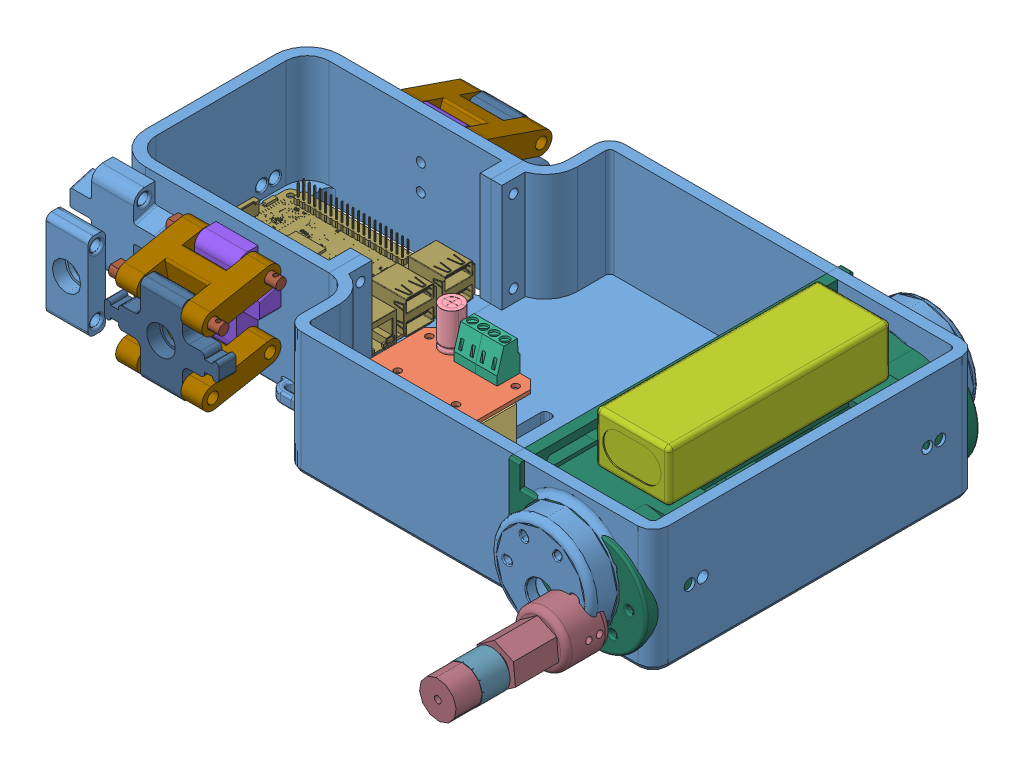
SolidWorks assembly Rover assembly, configuration Default. Lengths in mm.
Overall size (279 71 219.98).
23 component instances, 15 part files, 39 mates.
Components (placement in the parent):
- Chasis-1: Chasis [Default] at (-122.3049 -8.088 50.671) size (290 57 180)
- BTS7960 43A HIGH POWER H BRIDGE MODULE-1: BTS7960 43A HIGH POWER H BRIDGE MODULE [Default] at (-118.9354 21.912 91.3093) size (51 42.4 49.96)
  - PCB, BTS7960 43A HIGH POWER H BRIDGE MODULE-1: PCB, BTS7960 43A HIGH POWER H BRIDGE MODULE [Default] at origin size (49.5 1.7 49.8)
  - HEATSINK, BTS7960 43A HIGH POWER H BRIDGE MODULE-1: HEATSINK, BTS7960 43A HIGH POWER H BRIDGE MODULE [Default] at (0 0 2.4) size (51 23 32.02)
  - ALUMINUM ELECTROLYTIC CAPACITOR, 330 uF, BTS7960 43A HIGH POWER H BRIDGE MODULE-1: ALUMINUM ELECTROLYTIC CAPACITOR, 330 uF, BTS7960 43A HIGH POWER H BRIDGE MODULE [Default] at (-10.75 1.8 -19.85) x (0.999469 0 -0.032584) z (0.032584 0 0.999469) size (10.1 18.7 10.1)
  - 8 PIN HEADER, IC, BTS7960 43A HIGH POWER H BRIDGE MODULE-1: 8 PIN HEADER, IC, BTS7960 43A HIGH POWER H BRIDGE MODULE [Default] at (-34.78 4.2 20.29) x (0 0 -1) z (-1 0 0) size (5.08 11.6 10.16)
  - EUROSTYLE TERMINAL BLOCK 2 POS 5.0 MM RA PLUG, BTS7960 43A HIGH POWER H BRIDGE MODULE-1: EUROSTYLE TERMINAL BLOCK 2 POS 5.0 MM RA PLUG, BTS7960 43A HIGH POWER H BRIDGE MODULE [Default] at (0.75 4.2 -6.5) size (10 14.5 10.5)
  - EUROSTYLE TERMINAL BLOCK 2 POS 5.0 MM RA PLUG, BTS7960 43A HIGH POWER H BRIDGE MODULE-2: EUROSTYLE TERMINAL BLOCK 2 POS 5.0 MM RA PLUG, BTS7960 43A HIGH POWER H BRIDGE MODULE [Default] at (10.75 4.2 -6.5) size (10 14.5 10.5)
- Turnigy_2200mAh_3S_20C_Lipo_Pack-1: Turnigy_2200mAh_3S_20C_Lipo_Pack [Valor predeterminado] at (-16.3513 62.612 49.8832) x (0 0 -1) z (0 -1 0) size (103 34 24)
- SuspensionChasis-1: SuspensionChasis [Default] at (-74.5549 -10.088 50.671) size (40 40 10)
- SuspensionLink-1: SuspensionLink [Default] at (-204.5549 30.9653 112.9916) x (0 -0.187832 0.982201) z (0 0.982201 0.187832) size (37 40 10)
- SuspensionWheel-1: SuspensionWheel [Default] at (-74.0549 -7.4595 55.1905) size (53 40 8)
- SuspensionLink-2: SuspensionLink [Default] at (-204.5549 0.9653 112.9916) x (0 -0.187832 0.982201) z (0 0.982201 0.187832) size (37 40 10)
- SuspensionChasis-3: SuspensionChasis [Default] at (-335.0549 -10.088 50.671) x (-1 0 0) z (0 0 -1) size (40 40 10)
- SuspensionLink-5: SuspensionLink [Default] at (-204.5549 -0.7229 -10.4557) x (0 -0.326595 -0.945164) z (0 0.945164 -0.326595) size (37 40 10)
- SuspensionLink-6: SuspensionLink [Default] at (-204.5549 29.2771 -10.4557) x (0 -0.326595 -0.945164) z (0 0.945164 -0.326595) size (37 40 10)
- SuspensionWheel-3: SuspensionWheel [Default] at (-334.5549 -11.2061 47.1516) x (-1 0 0) z (0 0 -1) size (53 40 8)
- SuspensionPin-1: SuspensionPin [Default] at (-204.4549 38.412 100.671) size (50 4.8 6.8)
- SuspensionPin-2: SuspensionPin [Default] at (-204.4549 33.3405 127.1905) size (50 4.8 6.8)
- raspberryPi3B-1: raspberryPi3B [Detailed] at (-210.9061 -0.088 50.4075) x (1 0 0) z (0 1 0) size (87.05 58.5 18.55)
- 17HexHub(3.2shaft)-1: 17HexHub(3.2shaft) [Default] at (-6.8049 8.112 133.771) x (-0.093197 0.995648 0) z (0.995648 0.093197 0) size (25 67 25)
- RearWheelCap-1: RearWheelCap [Default] at (-6.8049 8.112 121.771) x (-0.923728 -0.383049 0) z (-0.383049 0.923728 0) size (17 12.9 17)
- 37D motor mount-1: 37D motor mount [Default] at (-26.7299 15.112 103.846) size (63.5 57.3 172.51)
Mates (geometry in assembly coordinates):
- Concentric1: concentric aligned: cylinder of Chasis-1 through (-19.3049 17.912 -44.329) axis (0 0 1) radius 7.5; cylinder of Titan-1 through (-19.3049 17.912 -23.829) axis (0 0 1) radius 6.55
- Coincident1: coincident anti-aligned: plane of Chasis-1 through (10.6951 48.912 -19.329) normal (0 0 1); plane of Titan-1 through (-19.3049 17.912 -19.329) normal (0 0 -1)
- Concentric3: concentric aligned: cylinder of SuspensionChasis-1 through (-195.0549 38.412 100.671) axis (-1 0 0) radius 2.6; cylinder of SuspensionLink-1 through (-184.5549 38.412 100.671) axis (-1 0 0) radius 2.6
- Distance1: distance = 0.2 mm anti-aligned: plane of SuspensionLink-1 through (-214.7549 40.7873 114.8699) normal (1 0 0); plane of SuspensionChasis-1 through (-214.5549 -10.088 50.671) normal (-1 0 0)
- Concentric5: concentric aligned: cylinder of SuspensionLink-1 through (-184.5549 33.3405 127.1905) axis (-1 0 0) radius 2.6; cylinder of SuspensionWheel-1 through (-194.5549 33.3405 127.1905) axis (-1 0 0) radius 2.6
- Distance2: distance = 0.2 mm anti-aligned: plane of SuspensionLink-1 through (-194.3549 40.7873 114.8699) normal (-1 0 0); plane of SuspensionWheel-1 through (-194.5549 -7.4595 55.1905) normal (1 0 0)
- Concentric6: concentric aligned: cylinder of SuspensionChasis-1 through (-195.0549 8.412 100.671) axis (-1 0 0) radius 2.6; cylinder of SuspensionLink-2 through (-184.5549 8.412 100.671) axis (-1 0 0) radius 2.6
- Concentric7: concentric aligned: cylinder of SuspensionWheel-1 through (-194.5549 3.3405 127.1905) axis (-1 0 0) radius 2.6; cylinder of SuspensionLink-2 through (-184.5549 3.3405 127.1905) axis (-1 0 0) radius 2.6
- Distance3: distance = 0.2 mm anti-aligned: plane of SuspensionChasis-1 through (-214.5549 -10.088 50.671) normal (-1 0 0); plane of SuspensionLink-2 through (-214.7549 10.7873 114.8699) normal (1 0 0)
- Coincident8: coincident anti-aligned: plane of Chasis-1 through (-122.3049 -1.088 95.671) normal (0 0 1); plane of SuspensionChasis-1 through (-195.0549 -10.088 95.671) normal (0 0 -1)
- Concentric8: concentric aligned: cylinder of Chasis-1 through (-19.3049 17.912 145.671) axis (0 0 -1) radius 7.5; cylinder of Titan-2 through (-19.3049 17.912 125.171) axis (0 0 -1) radius 6.55
- Coincident12: coincident anti-aligned: plane of Chasis-1 through (-145.3049 48.912 120.671) normal (0 0 -1); plane of Titan-2 through (-19.3049 17.912 120.671) normal (0 0 1)
- Coincident14: coincident anti-aligned: plane of Chasis-1 through (-122.3049 -1.088 50.671) normal (0 1 0); plane of BTS7960 43A HIGH POWER H BRIDGE MODULE-1/HEATSINK, BTS7960 43A HIGH POWER H BRIDGE MODULE-1 through (-118.9354 -1.088 93.7093) normal (0 -1 0)
- Concentric9: concentric aligned: cylinder of Chasis-1 through (-204.8049 29.412 -24.329) axis (0 0 1) radius 2.1; cylinder of SuspensionChasis-1 through (-204.8049 29.412 95.671) axis (0 0 1) radius 2.1
- Concentric10: concentric aligned: cylinder of Chasis-1 through (-204.8049 17.412 -24.329) axis (0 0 1) radius 2.1; cylinder of SuspensionChasis-1 through (-204.8049 17.412 95.671) axis (0 0 1) radius 2.1
- Concentric11: concentric aligned: cylinder of SuspensionChasis-3 through (-214.5549 38.412 0.671) axis (1 0 0) radius 2.6; cylinder of SuspensionLink-6 through (-224.5549 38.412 0.671) axis (1 0 0) radius 2.6
- Distance13: distance = 0.2 mm anti-aligned: plane of SuspensionLink-6 through (-214.7549 38.7288 -13.7217) normal (1 0 0); plane of SuspensionChasis-3 through (-214.5549 -10.088 50.671) normal (-1 0 0)
- Concentric12: concentric aligned: cylinder of SuspensionChasis-3 through (-214.5549 8.412 0.671) axis (1 0 0) radius 2.6; cylinder of SuspensionLink-5 through (-224.5549 8.412 0.671) axis (1 0 0) radius 2.6
- Distance14: distance = 0.2 mm anti-aligned: plane of SuspensionLink-5 through (-214.7549 8.7288 -13.7217) normal (1 0 0); plane of SuspensionChasis-3 through (-214.5549 -10.088 50.671) normal (-1 0 0)
- Concentric13: concentric aligned: cylinder of SuspensionLink-6 through (-224.5549 29.5939 -24.8484) axis (1 0 0) radius 2.6; cylinder of SuspensionWheel-3 through (-214.0549 29.5939 -24.8484) axis (1 0 0) radius 2.6
- Concentric14: concentric aligned: cylinder of SuspensionLink-5 through (-224.5549 -0.4061 -24.8484) axis (1 0 0) radius 2.6; cylinder of SuspensionWheel-3 through (-214.0549 -0.4061 -24.8484) axis (1 0 0) radius 2.6
- Distance15: distance = 0.2 mm anti-aligned: plane of SuspensionWheel-3 through (-194.5549 -11.2061 47.1516) normal (1 0 0); plane of SuspensionLink-6 through (-194.3549 38.7288 -13.7217) normal (-1 0 0)
- Concentric15: concentric anti-aligned: cylinder of Chasis-1 through (-204.8049 29.412 -24.329) axis (0 0 1) radius 2.1; cylinder of SuspensionChasis-3 through (-204.8049 29.412 5.671) axis (0 0 -1) radius 2.1
- Concentric16: concentric anti-aligned: cylinder of Chasis-1 through (-204.8049 17.412 -24.329) axis (0 0 1) radius 2.1; cylinder of SuspensionChasis-3 through (-204.8049 17.412 5.671) axis (0 0 -1) radius 2.1
- Coincident24: coincident anti-aligned: plane of Chasis-1 through (-122.3049 -1.088 5.671) normal (0 0 -1); plane of SuspensionChasis-3 through (-214.5549 -10.088 5.671) normal (0 0 1)
- Concentric17: concentric aligned: cylinder of SuspensionLink-1 through (-184.5549 38.412 100.671) axis (-1 0 0) radius 2.6; cylinder of SuspensionPin-1 through (-179.4549 38.412 100.671) axis (-1 0 0) radius 2.4
- Coincident25: coincident anti-aligned: plane of SuspensionLink-1 through (-224.5549 40.7873 114.8699) normal (-1 0 0); plane of SuspensionPin-1 through (-224.5549 38.412 100.671) normal (1 0 0)
- Concentric18: concentric aligned: cylinder of SuspensionLink-1 through (-184.5549 33.3405 127.1905) axis (-1 0 0) radius 2.6; cylinder of SuspensionPin-2 through (-179.4549 33.3405 127.1905) axis (-1 0 0) radius 2.4
- Coincident26: coincident anti-aligned: plane of SuspensionLink-1 through (-224.5549 40.7873 114.8699) normal (-1 0 0); plane of SuspensionPin-2 through (-224.5549 33.3405 127.1905) normal (1 0 0)
- Coincident27: coincident anti-aligned: plane of Chasis-1 through (-122.3049 -1.088 50.671) normal (0 1 0); plane of raspberryPi3B-1 through (-210.9061 -1.088 50.4075) normal (0 -1 0)
- Concentric19: concentric aligned: cylinder of Titan-2 through (-19.3049 17.912 141.871) axis (0 0 -1) radius 1.6; cylinder of 17HexHub(3.2shaft)-1 through (-6.8049 8.112 185.771) axis (0 0 -1) radius 3
- Concentric20: concentric aligned: cylinder of 17HexHub(3.2shaft)-1 through (-6.8049 8.112 185.771) axis (0 0 -1) radius 5.95; cylinder of RearWheelCap-1 through (-6.8049 8.112 188.771) axis (0 0 -1) radius 6
- Coincident31: coincident anti-aligned: plane of 17HexHub(3.2shaft)-1 through (-6.8049 8.112 185.771) normal (0 0 1); plane of RearWheelCap-1 through (-6.8049 8.112 185.771) normal (0 0 -1)
- Coincident32: coincident anti-aligned: plane of Chasis-1 through (-46.8049 -8.088 50.671) normal (1 0 0); plane of 37D motor mount-1 through (-46.8049 15.112 103.771) normal (-1 0 0)
- Coincident33: coincident aligned: circle of Chasis-1; circle of 37D motor mount-1
- Coincident34: coincident anti-aligned: circle of Chasis-1; circle of 37D motor mount-1
- Concentric24: concentric aligned: circle of 17HexHub(3.2shaft)-1; circle of 37D motor mount-1
- Coincident40: coincident anti-aligned: plane of 17HexHub(3.2shaft)-1 through (-6.8049 8.112 133.771) normal (0 0 -1); plane of 37D motor mount-1 through (-6.8049 15.112 133.771) normal (0 0 1)
- Coincident41: coincident anti-aligned: plane of Turnigy_2200mAh_3S_20C_Lipo_Pack-1 through (-16.3513 38.612 49.8832) normal (0 -1 0); plane of 37D motor mount-1 through (-26.7299 38.612 103.771) normal (0 1 0)
